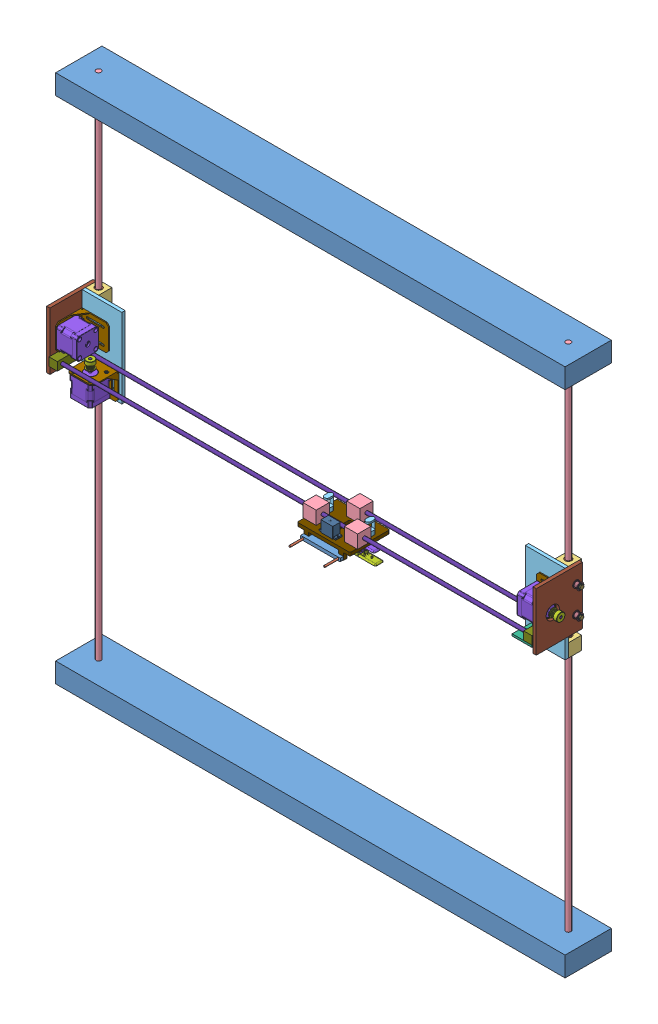
SolidWorks assembly Base Assembly, configuration Default. Lengths in mm.
Overall size (977.9 1016 174.63).
110 component instances, 29 part files, 80 mates.
Components (placement in the parent):
- Wood support-1: Wood support [Default] at (-151.6885 381.3846 556.984) size (977.9 38.1 88.9)
- Wood support-3: Wood support [Default] at (-151.6885 1397.3846 645.884) x (1 0 0) z (0 0 -1) size (977.9 38.1 88.9)
- Wood block w fitting-1: Wood block w fitting [Default] at (-133.7789 1048.2324 617.7695) x (0 0 -1) z (0 -1 0) size (25.4 25.4 25.4)
  - Bronze fitting-1: Bronze fitting [Default] at (16.3355 20.1904 11.168) size (12.7 12.7 25.4)
  - Wood block-1: Wood block [Default] at (3.6355 7.4904 11.168) size (25.4 25.4 25.4)
- Wood block w fitting-2: Wood block w fitting [Default] at (-133.7789 921.2324 617.7695) x (0 0 -1) z (0 -1 0) size (25.4 25.4 25.4)
  - Bronze fitting-1: Bronze fitting [Default] at (16.3355 20.1904 11.168) size (12.7 12.7 25.4)
  - Wood block-1: Wood block [Default] at (3.6355 7.4904 11.168) size (25.4 25.4 25.4)
- Wood block w fitting-3: Wood block w fitting [Default] at (808.3019 1048.2324 585.0985) x (0 0 1) z (0 -1 0) size (25.4 25.4 25.4)
  - Bronze fitting-1: Bronze fitting [Default] at (16.3355 20.1904 11.168) size (12.7 12.7 25.4)
  - Wood block-1: Wood block [Default] at (3.6355 7.4904 11.168) size (25.4 25.4 25.4)
- Wood block w fitting-4: Wood block w fitting [Default] at (808.3019 921.2324 585.0985) x (0 0 1) z (0 -1 0) size (25.4 25.4 25.4)
  - Bronze fitting-1: Bronze fitting [Default] at (16.3355 20.1904 11.168) size (12.7 12.7 25.4)
  - Wood block-1: Wood block [Default] at (3.6355 7.4904 11.168) size (25.4 25.4 25.4)
- Steel Rod-1: Steel Rod [Default] at (-113.5885 1397.3846 601.434) x (0.921856 0 -0.387532) z (0 -1 0) size (9.53 9.53 1016)
- Steel Rod-2: Steel Rod [Default] at (788.1115 1397.3846 601.434) x (-0.979084 0 0.203454) z (0 -1 0) size (9.53 9.53 1016)
- Support piece 2-1: Support piece 2 [Default] at (-88.1885 960.8644 614.134) x (0 -1 0) z (-1 0 0) size (152.4 6.35 76.2)
- Assem1-1: Assem1 [Default] at (-363.1535 852.2407 468.4599) x (0 1 0) z (1 0 0) size (110.49 88.9 75.3)
  - Stepper Motor Assembly-1: Stepper Motor Assembly [Default] at (-2.6319 57.0939 61.9281) size (50 51.29 75.3)
    - Screw-1: Screw [Default] at (147.7106 140.4303 199.9369) x (-0.047434 -0.998874 0) z (0.998874 -0.047434 0) size (7 25.04 7)
    - GT2_Pulley20_Teeth.stp-1: GT2_Pulley20_Teeth.stp [Default] at (132.2106 125.0707 168.6369) x (-0.679392 0.733775 0) z (0 0 -1) size (16 16 16)
    - NEMA_17_Stepper_Motor.step-1: NEMA_17_Stepper_Motor.step [Default] at (136.9106 140.0707 -883.0631) size (42.3 42.3 63.3)
    - Nema17_Mounting_Bracket-1: Nema17_Mounting_Bracket [Default] at (157.2106 94.9303 174.9369) x (0 0 1) z (-1 0 0) size (53 51 50)
    - Screw-2: Screw [Default] at (116.7106 109.4303 199.8369) x (1 0 0) z (0 1 0) size (7 25.04 7)
    - Screw.step-2: Screw.step [Default] at (147.7106 109.4303 199.9369) x (1 0 0) z (0 1 0) size (7 25.04 7)
    - Screw.step-3: Screw.step [Default] at (116.7106 140.5707 199.9369) x (-1 0 0) z (0 -1 0) size (7 25.04 7)
  - Support Piece-1: Support Piece [Default] at (184.8237 213.7741 230.515) x (-1 0 0) z (0 1 0) size (110.49 6.35 88.9)
  - Hexagonal Bolt M4-25-1: Hexagonal Bolt M4-25 [Default] at (154.9787 137.5741 221.761) x (0 0 1) z (-0.984688 0.174326 0) size (22.54 7 8.08)
    - Hexagonal Bolt M4-25-1: Hexagonal Bolt M4-25 [Default] at origin size (28.05 7 8.08)
  - GT2_Pulley_No_Teeth.step-1: GT2_Pulley_No_Teeth.step [Default] at (153.5262 139.0817 213.265) x (-0.999997 0.002516 0) z (0 0 1) size (13 13 8.5)
  - GT2_Pulley_No_Teeth.step-2: GT2_Pulley_No_Teeth.step [Default] at (102.2066 138.2764 239.011) x (-0.414322 0.91013 0) z (0 0 -1) size (13 13 8.5)
  - Hexagonal Bolt M4-25-4: Hexagonal Bolt M4-25 [Default] at (104.1787 137.5741 221.507) x (0 0 1) z (-0.959769 0.280791 0) size (22.54 7 8.08)
    - Hexagonal Bolt M4-25-1: Hexagonal Bolt M4-25 [Default] at origin size (28.05 7 8.08)
  - Washer-1: Washer [Default] at (104.1787 137.5741 230.515) x (1 0 0) z (0 1 0) size (9.53 0.25 9.53)
  - Washer-2: Washer [Default] at (154.9787 137.5741 230.515) x (1 0 0) z (0 1 0) size (9.53 0.25 9.53)
  - Washer-3: Washer [Default] at (104.1787 137.5741 221.507) x (0.130919 0.991393 0) z (0.991393 -0.130919 0) size (9.53 0.25 9.53)
  - Washer-4: Washer [Default] at (154.9787 137.5741 221.761) x (0.849495 -0.527597 0) z (-0.527597 -0.849495 0) size (9.53 0.25 9.53)
  - Washer-5: Washer [Default] at (104.1787 137.5741 237.119) x (0.704272 0.70993 0) z (-0.70993 0.704272 0) size (9.53 0.25 9.53)
  - Washer-6: Washer [Default] at (154.9787 137.5741 237.119) x (1 0 0) z (0 1 0) size (9.53 0.25 9.53)
  - Hexagonal Nut M4-1: Hexagonal Nut M4 [Default] at (154.99 137.5786 237.119) x (0.949988 -0.312286 0) z (-0.312286 -0.949988 0) size (7 3.45 8.08)
    - Hexagonal Nut M4-1: Hexagonal Nut M4 [Default] x (0 -1 0) z (-1 0 0) size (3.45 8.08 7)
  - Hexagonal Nut M4-2: Hexagonal Nut M4 [Default] at (104.196 137.5251 237.119) x (0.955479 -0.29506 0) z (-0.29506 -0.955479 0) size (7 3.45 8.08)
    - Hexagonal Nut M4-1: Hexagonal Nut M4 [Default] x (0 -1 0) z (-1 0 0) size (3.45 8.08 7)
- Stepper Motor Assembly-1: Stepper Motor Assembly [Default] at (-212.6756 1112.6013 525.5537) x (1 0 0) z (0 -1 0) size (50 51.29 75.3)
  - Screw-1: Screw [Default] at (147.7106 140.4303 199.9369) x (-0.047434 -0.998874 0) z (0.998874 -0.047434 0) size (7 25.04 7)
  - GT2_Pulley20_Teeth.stp-1: GT2_Pulley20_Teeth.stp [Default] at (132.2106 125.0707 168.6369) x (-0.679392 0.733775 0) z (0 0 -1) size (16 16 16)
  - NEMA_17_Stepper_Motor.step-1: NEMA_17_Stepper_Motor.step [Default] at (136.9106 140.0707 -883.0631) size (42.3 42.3 63.3)
  - Nema17_Mounting_Bracket-1: Nema17_Mounting_Bracket [Default] at (157.2106 94.9303 174.9369) x (0 0 1) z (-1 0 0) size (53 51 50)
  - Screw-2: Screw [Default] at (116.7106 109.4303 199.8369) x (1 0 0) z (0 1 0) size (7 25.04 7)
  - Screw.step-2: Screw.step [Default] at (147.7106 109.4303 199.9369) x (1 0 0) z (0 1 0) size (7 25.04 7)
  - Screw.step-3: Screw.step [Default] at (116.7106 140.5707 199.9369) x (-1 0 0) z (0 -1 0) size (7 25.04 7)
- Assem1-2: Assem1 [Default] at (1037.6765 1111.3981 468.4599) x (0 -1 0) z (-1 0 0) size (110.49 88.9 75.3)
  - Stepper Motor Assembly-1: Stepper Motor Assembly [Default] at (-2.6319 57.0939 61.9281) size (50 51.29 75.3)
    - Screw-1: Screw [Default] at (147.7106 140.4303 199.9369) x (-0.047434 -0.998874 0) z (0.998874 -0.047434 0) size (7 25.04 7)
    - GT2_Pulley20_Teeth.stp-1: GT2_Pulley20_Teeth.stp [Default] at (132.2106 125.0707 168.6369) x (-0.679392 0.733775 0) z (0 0 -1) size (16 16 16)
    - NEMA_17_Stepper_Motor.step-1: NEMA_17_Stepper_Motor.step [Default] at (136.9106 140.0707 -883.0631) size (42.3 42.3 63.3)
    - Nema17_Mounting_Bracket-1: Nema17_Mounting_Bracket [Default] at (157.2106 94.9303 174.9369) x (0 0 1) z (-1 0 0) size (53 51 50)
    - Screw-2: Screw [Default] at (116.7106 109.4303 199.8369) x (1 0 0) z (0 1 0) size (7 25.04 7)
    - Screw.step-2: Screw.step [Default] at (147.7106 109.4303 199.9369) x (1 0 0) z (0 1 0) size (7 25.04 7)
    - Screw.step-3: Screw.step [Default] at (116.7106 140.5707 199.9369) x (-1 0 0) z (0 -1 0) size (7 25.04 7)
  - Support Piece-1: Support Piece [Default] at (184.8237 213.7741 230.515) x (-1 0 0) z (0 1 0) size (110.49 6.35 88.9)
  - Hexagonal Bolt M4-25-1: Hexagonal Bolt M4-25 [Default] at (154.9787 137.5741 221.761) x (0 0 1) z (-0.984688 0.174326 0) size (22.54 7 8.08)
    - Hexagonal Bolt M4-25-1: Hexagonal Bolt M4-25 [Default] at origin size (28.05 7 8.08)
  - GT2_Pulley_No_Teeth.step-1: GT2_Pulley_No_Teeth.step [Default] at (153.5262 139.0817 213.265) x (-0.999997 0.002516 0) z (0 0 1) size (13 13 8.5)
  - GT2_Pulley_No_Teeth.step-2: GT2_Pulley_No_Teeth.step [Default] at (102.2066 138.2764 239.011) x (-0.414322 0.91013 0) z (0 0 -1) size (13 13 8.5)
  - Hexagonal Bolt M4-25-4: Hexagonal Bolt M4-25 [Default] at (104.1787 137.5741 221.507) x (0 0 1) z (-0.959769 0.280791 0) size (22.54 7 8.08)
    - Hexagonal Bolt M4-25-1: Hexagonal Bolt M4-25 [Default] at origin size (28.05 7 8.08)
  - Washer-1: Washer [Default] at (104.1787 137.5741 230.515) x (1 0 0) z (0 1 0) size (9.53 0.25 9.53)
  - Washer-2: Washer [Default] at (154.9787 137.5741 230.515) x (1 0 0) z (0 1 0) size (9.53 0.25 9.53)
  - Washer-3: Washer [Default] at (104.1787 137.5741 221.507) x (0.130919 0.991393 0) z (0.991393 -0.130919 0) size (9.53 0.25 9.53)
  - Washer-4: Washer [Default] at (154.9787 137.5741 221.761) x (0.849495 -0.527597 0) z (-0.527597 -0.849495 0) size (9.53 0.25 9.53)
  - Washer-5: Washer [Default] at (104.1787 137.5741 237.119) x (0.704272 0.70993 0) z (-0.70993 0.704272 0) size (9.53 0.25 9.53)
  - Washer-6: Washer [Default] at (154.9787 137.5741 237.119) x (1 0 0) z (0 1 0) size (9.53 0.25 9.53)
  - Hexagonal Nut M4-1: Hexagonal Nut M4 [Default] at (154.99 137.5786 237.119) x (0.949988 -0.312286 0) z (-0.312286 -0.949988 0) size (7 3.45 8.08)
    - Hexagonal Nut M4-1: Hexagonal Nut M4 [Default] x (0 -1 0) z (-1 0 0) size (3.45 8.08 7)
  - Hexagonal Nut M4-2: Hexagonal Nut M4 [Default] at (104.196 137.5251 237.119) x (0.955479 -0.29506 0) z (-0.29506 -0.955479 0) size (7 3.45 8.08)
    - Hexagonal Nut M4-1: Hexagonal Nut M4 [Default] x (0 -1 0) z (-1 0 0) size (3.45 8.08 7)
- Support piece 2-2: Support piece 2 [Default] at (762.7115 960.8644 614.134) x (0 -1 0) z (-1 0 0) size (152.4 6.35 76.2)
- Wood block 2-1: Wood block 2 [Default] at (-118.351 948.8819 620.484) x (0 1 0) z (1 0 0) size (15.88 63.5 15.88)
- Wood block 2-2: Wood block 2 [Default] at (792.874 948.8819 620.484) x (0 -1 0) z (-1 0 0) size (15.88 63.5 15.88)
- Small Steel Rod-1: Small Steel Rod [Default] at (794.4615 948.8819 674.459) x (0 0.1575 0.987519) z (-1 0 0) size (6.35 6.35 914.4)
- Small Steel Rod-2: Small Steel Rod [Default] at (794.4615 948.8819 630.009) x (0 -0.084822 0.996396) z (-1 0 0) size (6.35 6.35 914.4)
- Drawing Mount Assembly-1: Drawing Mount Assembly [Default] at (377.0255 980.202 732.2531) x (1 0 0) z (0 0 -1) size (101.6 22.23 107.95)
  - Drawing Mount-1: Drawing Mount [Default] at (39.6439 44.0201 83.1941) size (101.6 21.18 76.2)
  - Drawing mount 2-1: Drawing mount 2 [Default] at (39.7074 56.7201 62.1343) size (76.2 9.53 69.85)
  - 0.125 Dowel pin-1: 0.125 Dowel pin [Default] at (6.3064 59.8951 0.6441) x (0.801473 -0.598031 0) z (0 0 1) size (3.17 3.17 101.6)
  - 0.125 Dowel pin-2: 0.125 Dowel pin [Default] at (72.9814 59.8951 0.6441) x (0.816688 0.577079 0) z (0 0 1) size (3.17 3.17 101.6)
  - Spring-1: Spring [Default] at (6.3064 59.8951 38.9981) x (0.94588 -0.324516 0) z (-0.324516 -0.94588 0) size (3.43 38.61 3.96)
  - Spring-2: Spring [Default] at (72.9814 59.8951 38.9981) x (-0.31762 -0.948218 0) z (-0.948218 0.31762 0) size (3.43 38.61 3.96)
- Wood Support 3-1: Wood Support 3 [Default] at (377.0157 948.8819 661.759) x (1 0 0) z (0 -1 0) size (25.4 25.4 31.75)
- Wood Support 3-2: Wood Support 3 [Default] at (456.4698 948.8819 661.759) x (1 0 0) z (0 -1 0) size (25.4 25.4 31.75)
- Wood Support 3-3: Wood Support 3 [Default] at (416.6072 948.8819 617.309) x (1 0 0) z (0 -1 0) size (25.4 25.4 31.75)
- GT2 Belt support-1: GT2 Belt support [Default] at (377.0157 953.7079 653.8778) x (-1 0 0) z (0 -1 0) size (9.53 15.88 31.75)
- GT2 Belt support-2: GT2 Belt support [Default] at (456.4698 953.7079 653.8778) x (-1 0 0) z (0 -1 0) size (9.53 15.88 31.75)
- Pulley Support-1: Pulley Support [Default] at (760.8789 911.6392 618.5095) size (38.1 22.54 63.5)
  - Wood support 4-1: Wood support 4 [Default] at (1.8326 25.4952 65.4745) size (38.1 3.81 63.5)
  - Hexagonal Bolt M4-25-1: Hexagonal Bolt M4-25 [Default] at (21.0153 38.3132 36.8995) x (0 -1 0) z (0 0 1) size (22.54 7 8.08)
    - Hexagonal Bolt M4-25-1: Hexagonal Bolt M4-25 [Default] at origin size (28.05 7 8.08)
  - Washer-1: Washer [Default] at (21.0153 38.3132 36.8995) x (-0.092668 0 -0.995697) z (-0.995697 0 0.092668) size (9.53 0.25 9.53)
  - Washer-2: Washer [Default] at (21.0153 25.4952 36.8995) size (9.53 0.25 9.53)
  - Hexagonal Nut M4-1: Hexagonal Nut M4 [Default] at (21.0153 25.4952 36.8995) x (-0.769257 0 0.638939) z (0.638939 0 0.769257) size (7 3.45 8.08)
    - Hexagonal Nut M4-1: Hexagonal Nut M4 [Default] x (0 -1 0) z (-1 0 0) size (3.45 8.08 7)
  - GT2_Pulley_No_Teeth.step-1: GT2_Pulley_No_Teeth.step [Default] at (21.4088 20.8092 38.9557) x (0.836365 0 0.548174) z (0 1 0) size (13 13 8.5)
  - Washer-3: Washer [Default] at (21.0153 29.3052 36.8995) size (9.53 0.25 9.53)
- GT2 Belt support-3: GT2 Belt support [Default] at (-130.7738 1341.7586 602.2095) x (0 0 -1) z (0 1 0) size (9.53 15.88 31.75)
- Clamp Assembly-1: Clamp Assembly [Default] at (403.839 857.5499 582.5233) size (72.31 22.86 16.51)
  - Clamp 1-1: Clamp 1 [Default] at (-3.6913 33.5471 71.2954) size (69.85 15.24 16.51)
  - Clamp 2-1: Clamp 2 [Default] at (-6.1562 56.4071 54.7854) x (1 0 0) z (0 0 -1) size (69.85 15.24 16.51)
  - Clamp pin-1: Clamp pin [Default] at (36.5419 44.9771 54.7854) size (3.81 3.81 16.51)
- MG90S (1)-3: MG90S (1) [Défaut] at (428.8994 957.5819 694.409) x (-1 0 0) z (0 0 1) size (31.8 32.7 14.6)
Mates (geometry in assembly coordinates):
- Concentric1: concentric anti-aligned: circle of Wood support-1; circle of Wood support-3
- Parallel1: parallel aligned: plane of Wood support-1 through (-151.6885 381.3846 645.884) normal (0 0 1); plane of Wood support-3 through (-151.6885 1397.3846 645.884) normal (0 0 1)
- Concentric4: concentric aligned: circle of Wood support-3; circle of Steel Rod-2
- Concentric5: concentric aligned: cylinder of Wood block w fitting-3/Bronze fitting-1 through (788.1115 1011.6644 601.434) axis (0 1 0) radius 4.7625; cylinder of Steel Rod-2 through (788.1115 381.3846 601.434) axis (0 1 0) radius 4.7625
- Concentric6: concentric aligned: cylinder of Wood block w fitting-4/Bronze fitting-1 through (788.1115 884.6644 601.434) axis (0 1 0) radius 4.7625; cylinder of Steel Rod-2 through (788.1115 381.3846 601.434) axis (0 1 0) radius 4.7625
- Concentric7: concentric aligned: circle of Wood support-3; circle of Steel Rod-1
- Concentric8: concentric aligned: cylinder of Wood block w fitting-1/Bronze fitting-1 through (-113.5885 1011.6644 601.434) axis (0 1 0) radius 4.7625; cylinder of Steel Rod-1 through (-113.5885 381.3846 601.434) axis (0 1 0) radius 4.7625
- Concentric9: concentric aligned: cylinder of Wood block w fitting-2/Bronze fitting-1 through (-113.5885 884.6644 601.434) axis (0 1 0) radius 4.7625; cylinder of Steel Rod-1 through (-113.5885 381.3846 601.434) axis (0 1 0) radius 4.7625
- Parallel8: parallel aligned: plane of Wood block w fitting-1/Wood block-1 through (-100.8885 1011.6644 614.134) normal (1 0 0); plane of Wood block w fitting-2/Wood block-1 through (-100.8885 884.6644 614.134) normal (1 0 0)
- Parallel9: parallel aligned: plane of Wood block w fitting-3/Wood block-1 through (775.4115 1011.6644 588.734) normal (-1 0 0); plane of Wood block w fitting-4/Wood block-1 through (775.4115 884.6644 588.734) normal (-1 0 0)
- Coincident27: coincident aligned: plane of Wood support-3 through (-151.6885 1397.3846 556.984) normal (0 1 0); plane of Steel Rod-2 through (788.1115 1397.3846 601.434) normal (0 1 0)
- Coincident28: coincident aligned: plane of Wood support-3 through (-151.6885 1397.3846 556.984) normal (0 1 0); plane of Steel Rod-1 through (-113.5885 1397.3846 601.434) normal (0 1 0)
- Coincident29: coincident aligned: plane of Wood support-1 through (-151.6885 381.3846 645.884) normal (0 -1 0); plane of Steel Rod-1 through (-113.5885 381.3846 601.434) normal (0 -1 0)
- Coincident31: coincident anti-aligned: plane of Wood block w fitting-1/Wood block-1 through (-126.2885 1011.6644 614.134) normal (0 0 1); plane of Support piece 2-1 through (-88.1885 960.8644 614.134) normal (0 0 -1)
- Coincident32: coincident anti-aligned: plane of Wood block w fitting-2/Wood block-1 through (-126.2885 884.6644 614.134) normal (0 0 1); plane of Support piece 2-1 through (-88.1885 960.8644 614.134) normal (0 0 -1)
- Coincident33: coincident aligned: line of Wood block w fitting-1/Wood block-1 through (-100.8885 1037.0644 614.134) axis (-1 0 0); line of Support piece 2-1 through (-50.0885 1037.0644 614.134) axis (-1 0 0)
- Parallel13: parallel aligned: line of Wood block w fitting-1/Wood block-1 through (-100.8885 1011.6644 614.134) axis (0 1 0); line of Support piece 2-1 through (-50.0885 884.6644 620.484) axis (0 1 0)
- Parallel14: parallel anti-aligned: line of Wood block w fitting-2/Wood block-1 through (-100.8885 884.6644 614.134) axis (-1 0 0); line of Support piece 2-1 through (-126.2885 884.6644 620.484) axis (1 0 0)
- Coincident36: coincident anti-aligned: line of Wood block w fitting-2/Wood block-1 through (-100.8885 884.6644 614.134) axis (-1 0 0); line of Support piece 2-1 through (-126.2885 884.6644 614.134) axis (1 0 0)
- Parallel18: parallel aligned: plane of Wood support-3 through (-151.6885 1397.3846 645.884) normal (0 0 1); plane of Support piece 2-1 through (-88.1885 960.8644 620.484) normal (0 0 1)
- Coincident49: coincident anti-aligned: plane of Support piece 2-1 through (-88.1885 960.8644 620.484) normal (0 0 1); plane of Assem1-1/Stepper Motor Assembly-1/Nema17_Mounting_Bracket-1 through (-73.2885 956.8194 620.484) normal (0 0 -1)
- Coincident51: coincident anti-aligned: plane of Support piece 2-1 through (-126.2885 884.6644 620.484) normal (-1 0 0); plane of Assem1-1/Support Piece-1 through (-126.2885 1037.0644 682.234) normal (1 0 0)
- Parallel19: parallel anti-aligned: plane of Support piece 2-1 through (-88.1885 960.8644 620.484) normal (0 0 1); plane of Stepper Motor Assembly-1/Nema17_Mounting_Bracket-1 through (-105.465 884.6644 620.484) normal (0 0 -1)
- Parallel20: parallel aligned: plane of Support piece 2-1 through (-126.2885 884.6644 620.484) normal (0 -1 0); plane of Stepper Motor Assembly-1/Nema17_Mounting_Bracket-1 through (-105.465 884.6644 622.484) normal (0 -1 0)
- Parallel21: parallel aligned: plane of Support piece 2-1 through (-126.2885 884.6644 620.484) normal (-1 0 0); plane of Stepper Motor Assembly-1/Nema17_Mounting_Bracket-1 through (-105.465 937.6644 620.484) normal (-1 0 0)
- Coincident56: coincident anti-aligned: plane of Support piece 2-1 through (-88.1885 960.8644 620.484) normal (0 0 1); plane of Stepper Motor Assembly-1/Nema17_Mounting_Bracket-1 through (-105.465 884.6644 620.484) normal (0 0 -1)
- Coincident57: coincident aligned: line of Support piece 2-1 through (-126.2885 884.6644 620.484) axis (1 0 0); line of Stepper Motor Assembly-1/Nema17_Mounting_Bracket-1 through (-100.465 884.6644 620.484) axis (1 0 0)
- Coincident58: coincident aligned: plane of Wood block w fitting-1/Wood block-1 through (-126.2885 1037.0644 614.134) normal (0 1 0); plane of Assem1-1/Support Piece-1 through (-126.2885 1037.0644 682.234) normal (0 1 0)
- Coincident59: coincident anti-aligned: line of Wood block w fitting-1/Wood block-1 through (-126.2885 1037.0644 614.134) axis (0 0 -1); line of Assem1-1/Support Piece-1 through (-126.2885 1037.0644 593.334) axis (0 0 1)
- Parallel22: parallel anti-aligned: plane of Wood block w fitting-3/Wood block-1 through (800.8115 1011.6644 614.134) normal (0 0 1); plane of Support piece 2-2 through (762.7115 960.8644 614.134) normal (0 0 -1)
- Coincident61: coincident anti-aligned: plane of Wood block w fitting-4/Wood block-1 through (800.8115 884.6644 614.134) normal (0 0 1); plane of Support piece 2-2 through (762.7115 960.8644 614.134) normal (0 0 -1)
- Coincident62: coincident anti-aligned: line of Wood block w fitting-4/Wood block-1 through (800.8115 884.6644 614.134) axis (-1 0 0); line of Support piece 2-2 through (724.6115 884.6644 614.134) axis (1 0 0)
- Coincident63: coincident aligned: line of Wood block w fitting-4/Wood block-1 through (800.8115 884.6644 614.134) axis (0 1 0); line of Support piece 2-2 through (800.8115 884.6644 614.134) axis (0 1 0)
- Coincident64: coincident aligned: line of Wood block w fitting-3/Wood block-1 through (800.8115 1037.0644 614.134) axis (-1 0 0); line of Support piece 2-2 through (800.8115 1037.0644 614.134) axis (-1 0 0)
- Parallel23: parallel aligned: plane of Wood support-3 through (-151.6885 1397.3846 645.884) normal (0 0 1); plane of Support piece 2-2 through (762.7115 960.8644 620.484) normal (0 0 1)
- Parallel24: parallel anti-aligned: plane of Wood block w fitting-3/Wood block-1 through (800.8115 1011.6644 588.734) normal (1 0 0); plane of Assem1-2/Support Piece-1 through (800.8115 926.5744 682.234) normal (-1 0 0)
- Coincident67: coincident anti-aligned: line of Wood block w fitting-3/Wood block-1 through (800.8115 1037.0644 588.734) axis (0 0 1); line of Assem1-2/Support Piece-1 through (800.8115 1037.0644 682.234) axis (0 0 -1)
- Coincident68: coincident anti-aligned: plane of Assem1-2/Stepper Motor Assembly-1/Nema17_Mounting_Bracket-1 through (747.8115 1006.8194 620.484) normal (0 0 -1); plane of Support piece 2-2 through (762.7115 960.8644 620.484) normal (0 0 1)
- Coincident71: coincident anti-aligned: plane of Support piece 2-1 through (-88.1885 960.8644 620.484) normal (0 0 1); plane of Wood block 2-1 through (-118.351 948.8819 620.484) normal (0 0 -1)
- Parallel25: parallel anti-aligned: plane of Assem1-1/Support Piece-1 through (-126.2885 1037.0644 682.234) normal (1 0 0); plane of Wood block 2-1 through (-126.2885 956.8194 683.984) normal (-1 0 0)
- Coincident73: coincident anti-aligned: plane of Assem1-1/Support Piece-1 through (-126.2885 1037.0644 682.234) normal (1 0 0); plane of Wood block 2-1 through (-126.2885 956.8194 683.984) normal (-1 0 0)
- Coincident74: coincident anti-aligned: plane of Assem1-1/Stepper Motor Assembly-1/Nema17_Mounting_Bracket-1 through (-126.2885 956.8194 620.484) normal (0 -1 0); plane of Wood block 2-1 through (-110.4135 956.8194 683.984) normal (0 1 0)
- Coincident75: coincident anti-aligned: plane of Assem1-2/Support Piece-1 through (800.8115 926.5744 682.234) normal (-1 0 0); plane of Wood block 2-2 through (800.8115 940.9444 683.984) normal (1 0 0)
- Coincident76: coincident anti-aligned: plane of Support piece 2-2 through (762.7115 960.8644 620.484) normal (0 0 1); plane of Wood block 2-2 through (792.874 948.8819 620.484) normal (0 0 -1)
- Coincident77: coincident anti-aligned: plane of Assem1-2/Stepper Motor Assembly-1/Nema17_Mounting_Bracket-1 through (800.8115 956.8194 620.484) normal (0 -1 0); plane of Wood block 2-2 through (784.9365 956.8194 683.984) normal (0 1 0)
- Concentric10: concentric aligned: circle of Wood block 2-2; circle of Small Steel Rod-1
- Coincident80: coincident anti-aligned: plane of Wood block 2-2 through (794.4615 948.8819 674.459) normal (-1 0 0); plane of Small Steel Rod-1 through (794.4615 948.8819 674.459) normal (1 0 0)
- Coincident81: coincident anti-aligned: plane of Wood block 2-1 through (-119.9385 948.8819 674.459) normal (1 0 0); plane of Small Steel Rod-1 through (-119.9385 948.8819 674.459) normal (-1 0 0)
- Concentric11: concentric anti-aligned: circle of Wood block 2-1; circle of Small Steel Rod-1
- Concentric12: concentric aligned: circle of Wood block 2-2; circle of Small Steel Rod-2
- Coincident84: coincident anti-aligned: plane of Wood block 2-2 through (794.4615 948.8819 630.009) normal (-1 0 0); plane of Small Steel Rod-2 through (794.4615 948.8819 630.009) normal (1 0 0)
- Concentric13: concentric aligned: cylinder of Small Steel Rod-1 through (-119.9385 948.8819 674.459) axis (1 0 0) radius 3.175; cylinder of Wood Support 3-1 through (364.3157 948.8819 674.459) axis (1 0 0) radius 3.175
- Parallel26: parallel aligned: plane of Wood support-3 through (-151.6885 1397.3846 645.884) normal (0 0 1); plane of Wood Support 3-1 through (377.0157 948.8819 687.159) normal (0 0 1)
- Concentric14: concentric aligned: circle of Drawing Mount Assembly-1/Drawing Mount-1; circle of Wood Support 3-1
- Coincident89: coincident aligned: plane of Drawing Mount Assembly-1/Drawing Mount-1 through (416.6694 929.8319 649.059) normal (0 -1 0); plane of Wood Support 3-1 through (377.0157 929.8319 674.459) normal (0 -1 0)
- Concentric15: concentric aligned: cylinder of Small Steel Rod-1 through (-119.9385 948.8819 674.459) axis (1 0 0) radius 3.175; cylinder of Wood Support 3-2 through (443.7698 948.8819 674.459) axis (1 0 0) radius 3.175
- Parallel27: parallel aligned: plane of Wood support-3 through (-151.6885 1397.3846 645.884) normal (0 0 1); plane of Wood Support 3-2 through (456.4698 948.8819 687.159) normal (0 0 1)
- Concentric16: concentric aligned: cylinder of Drawing Mount Assembly-1/Drawing Mount-1 through (456.4698 929.8319 674.459) axis (0 1 0) radius 3.175; cylinder of Wood Support 3-2 through (456.4698 929.8319 674.459) axis (0 1 0) radius 3.175
- Concentric17: concentric aligned: axis of Small Steel Rod-2 through (-119.9385 948.8819 630.009) axis (1 0 0); cylinder of Wood Support 3-3 through (403.9072 948.8819 630.009) axis (1 0 0) radius 3.175
- Parallel29: parallel aligned: plane of Wood support-3 through (-151.6885 1397.3846 556.984) normal (0 0 -1); plane of Wood Support 3-3 through (416.6072 948.8819 617.309) normal (0 0 -1)
- Concentric18: concentric aligned: cylinder of Drawing Mount Assembly-1/Drawing Mount-1 through (416.6072 929.8319 630.009) axis (0 1 0) radius 3.175; cylinder of Wood Support 3-3 through (416.6072 929.8319 630.009) axis (0 1 0) radius 3.175
- Parallel30: parallel aligned: plane of Wood Support 3-3 through (429.3072 961.5819 642.709) normal (0 1 0); plane of GT2 Belt support-1 through (377.0157 961.5819 647.5278) normal (0 1 0)
- Coincident97: coincident aligned: plane of Drawing Mount Assembly-1/Drawing Mount-1 through (416.6694 929.8319 649.059) normal (0 -1 0); plane of GT2 Belt support-1 through (377.0157 929.8319 653.8778) normal (0 -1 0)
- Concentric19: concentric aligned: circle of Drawing Mount Assembly-1/Drawing Mount-1; circle of GT2 Belt support-1
- Parallel31: parallel aligned: plane of Wood Support 3-3 through (403.9072 936.1819 642.709) normal (-1 0 0); plane of GT2 Belt support-1 through (373.8407 929.8319 653.8778) normal (-1 0 0)
- Parallel32: parallel aligned: plane of Wood Support 3-3 through (429.3072 961.5819 642.709) normal (0 1 0); plane of GT2 Belt support-2 through (456.4698 961.5819 647.5278) normal (0 1 0)
- Concentric24: concentric aligned: circle of Drawing Mount Assembly-1/Drawing Mount-1; circle of GT2 Belt support-2
- Coincident107: coincident aligned: plane of Drawing Mount Assembly-1/Drawing Mount-1 through (416.6694 929.8319 649.059) normal (0 -1 0); plane of GT2 Belt support-2 through (456.4698 929.8319 653.8778) normal (0 -1 0)
- Coincident108: coincident anti-aligned: plane of Assem1-2/Support Piece-1 through (800.8115 926.5744 682.234) normal (-1 0 0); plane of Pulley Support-1/Wood support 4-1 through (800.8115 940.9444 683.984) normal (1 0 0)
- Coincident109: coincident anti-aligned: plane of Support piece 2-2 through (762.7115 960.8644 620.484) normal (0 0 1); plane of Pulley Support-1/Wood support 4-1 through (762.7115 940.9444 620.484) normal (0 0 -1)
- Coincident110: coincident anti-aligned: plane of Wood block 2-2 through (784.9365 940.9444 683.984) normal (0 -1 0); plane of Pulley Support-1/Wood support 4-1 through (762.7115 940.9444 683.984) normal (0 1 0)
- Parallel35: parallel anti-aligned: plane of Wood support-3 through (-151.6885 1397.3846 556.984) normal (0 0 -1); plane of GT2 Belt support-3 through (-137.1238 1333.8846 606.972) normal (0 0 1)
- Parallel36: parallel aligned: plane of Wood support-3 through (-151.6885 1359.2846 556.984) normal (0 -1 0); plane of GT2 Belt support-3 through (-137.1238 1333.8846 602.2095) normal (0 -1 0)
- Coincident116: coincident anti-aligned: plane of Wood support-3 through (-151.6885 1359.2846 556.984) normal (0 -1 0); plane of GT2 Belt support-3 through (-137.1238 1359.2846 602.2095) normal (0 1 0)
- Concentric25: concentric aligned: circle of Drawing Mount Assembly-1/Drawing mount 2-1; circle of Clamp Assembly-1/Clamp 2-1
- Coincident129: coincident anti-aligned: plane of Drawing Mount Assembly-1/Drawing mount 2-1 through (416.7329 913.9569 645.5637) normal (0 -1 0); plane of Clamp Assembly-1/Clamp 2-1 through (397.6829 913.9569 637.3087) normal (0 1 0)
- Parallel43: parallel aligned: plane of Drawing Mount Assembly-1/Drawing Mount-1 through (416.6694 929.8319 699.859) normal (0 0 1); plane of Clamp Assembly-1/Clamp 2-1 through (397.6829 907.6069 653.8187) normal (0 0 1)
- Parallel47: parallel aligned: plane of Drawing Mount Assembly-1/Drawing Mount-1 through (416.6694 929.8319 699.859) normal (0 0 1); plane of MG90S (1)-3 through (428.8994 934.1819 694.409) normal (0 0 1)
- Concentric28: concentric anti-aligned: circle of Drawing Mount Assembly-1/Drawing Mount-1; circle of MG90S (1)-3
- Coincident137: coincident anti-aligned: plane of Drawing Mount Assembly-1/Drawing Mount-1 through (416.6694 936.1819 649.059) normal (0 1 0); plane of MG90S (1)-3 through (428.8994 936.1819 694.409) normal (0 -1 0)
